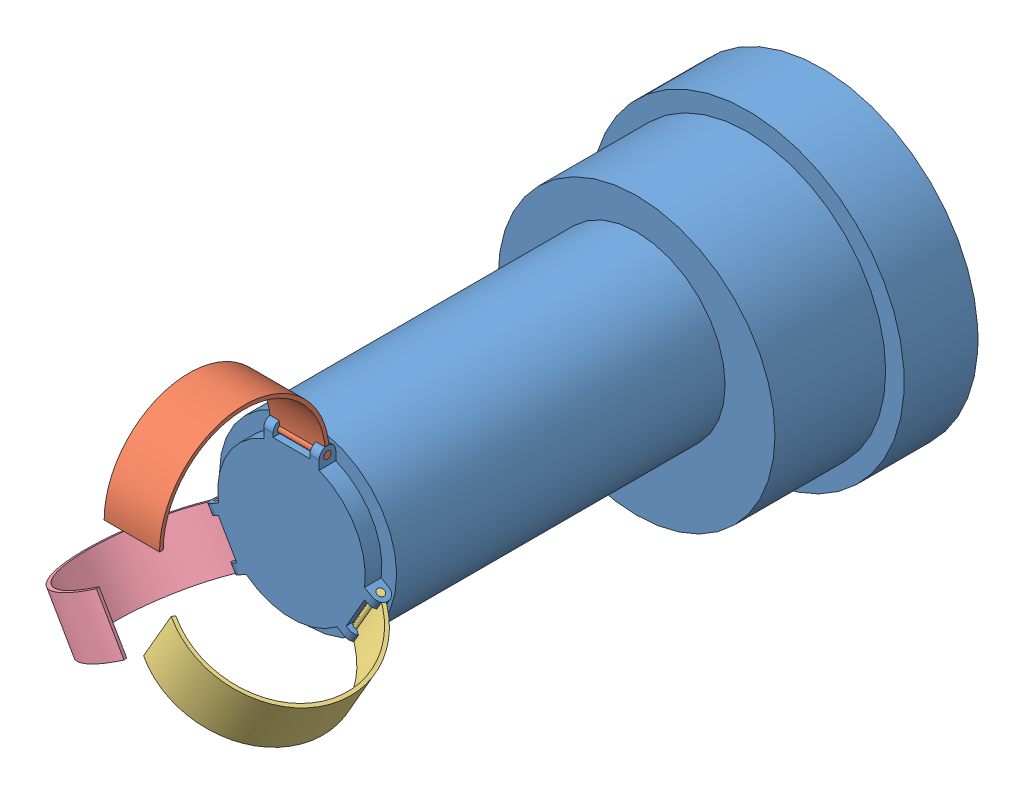
SolidWorks assembly Kirigami_gripper_gazebo, configuration ﾃﾞﾌｫﾙﾄ. Lengths in mm.
Overall size (85 91.5 196.25).
4 component instances, 4 part files, 10 mates.
Components (placement in the parent):
- kirigami_gripper_base-1: kirigami_gripper_base [ﾃﾞﾌｫﾙﾄ] at (6.3187 -3.2764 71.75) size (85 85 143.5)
- finger_1-1: finger_1 [ﾃﾞﾌｫﾙﾄ] at (13.8187 22.7236 213) x (0 1 0) z (-1 0 0) size (33 46.5 15)
- finger_2-1: finger_2 [ﾃﾞﾌｫﾙﾄ] at (20.7552 -15.2715 213) x (0.805976 -0.465331 0.365882) z (0.5 0.866025 0) size (33 46.5 15)
- finger_3-1: finger_3 [ﾃﾞﾌｫﾙﾄ] at (-15.6178 -2.2812 213) x (-0.833865 -0.481432 0.269985) z (0.5 -0.866025 0) size (33 46.5 15)
Mates (geometry in assembly coordinates):
- 一致1: coincident aligned: circle of kirigami_gripper_base-1; cylinder of finger_1-1 through (-1.1813 22.7236 213) axis (1 0 0) radius 1
- 一致2: coincident aligned: plane of kirigami_gripper_base-1 through (13.8187 11.7236 210.75) normal (1 0 0); plane of finger_1-1 through (13.8187 22.7236 213) normal (1 0 0)
- 同心円1: concentric anti-aligned: cylinder of kirigami_gripper_base-1 through (-6.6879 -62.8044 213) axis (0.5 0.866025 0) radius 1; cylinder of fingger_2-1 through (28.2552 -2.2812 213) axis (-0.5 -0.866025 0) radius 1
- 一致3: coincident aligned: plane of kirigami_gripper_base-1 through (11.2289 -9.7715 215.25) normal (-0.5 -0.866025 0); plane of fingger_2-1 through (20.7552 -15.2715 213) normal (-0.5 -0.866025 0)
- 同心円2: concentric anti-aligned: cylinder of kirigami_gripper_base-1 through (-38.7308 37.7517 213) axis (0.5 -0.866025 0) radius 1; cylinder of fingger_3-1 through (-8.1178 -15.2715 213) axis (-0.5 0.866025 0) radius 1
- 一致4: coincident aligned: plane of kirigami_gripper_base-1 through (-6.0916 3.2188 210.75) normal (-0.5 0.866025 0); plane of fingger_3-1 through (-15.6178 -2.2812 213) normal (-0.5 0.866025 0)
- Joint_limit_changer: planar angle = 0.45 rad aligned: line of finger_1-1 through (13.8187 22.7236 213) axis (0 0.204311 0.978906)
- Check_GripperOpen_joint_angle: planar angle = 0.10913 rad: line of assembly; line of assembly; line of finger_1-1 through (13.8187 22.7236 213) axis (0 0.204311 0.978906)
- Check_GripperClose_joint_angle: planar angle = 0.479327 rad aligned: line of finger_1-1 through (13.8187 22.7236 213) axis (0 0.204311 0.978906)
- Fix_finger_1: coincident aligned: line of finger_1-1 through (13.8187 22.7236 213) axis (0 0 1)
